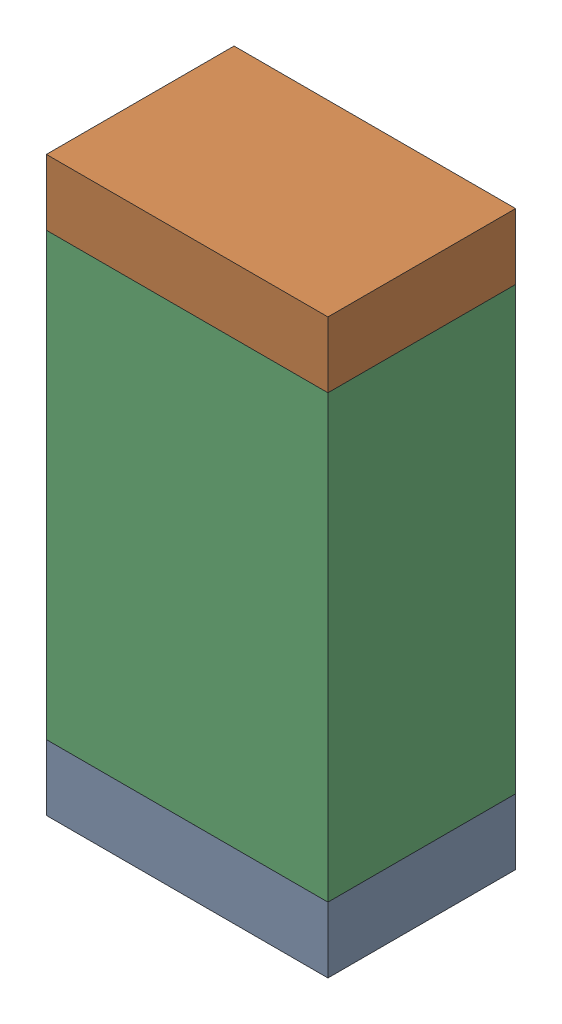
SolidWorks assembly R16, configuration Default. Lengths in mm.
Overall size (0.76 1.55 0.51).
6 component instances, 2 part files, 0 mates.
Components (placement in the parent):
- 822501776-1: 822501776 [Default] at (21.3176 19.0406 0) size (0.76 0.18 0.51)
  - Extruded_3-1: Extruded_3 [Default] at origin size (0.76 0.18 0.51)
- 822501776-2: 822501776 [Default] at (21.3176 20.4122 0) size (0.76 0.18 0.51)
  - Extruded_3-1: Extruded_3 [Default] at origin size (0.76 0.18 0.51)
- 822501912-1: 822501912 [Default] at (21.3176 19.7264 0) size (0.76 1.19 0.51)
  - Extruded_4-1: Extruded_4 [Default] at origin size (0.76 1.19 0.51)
